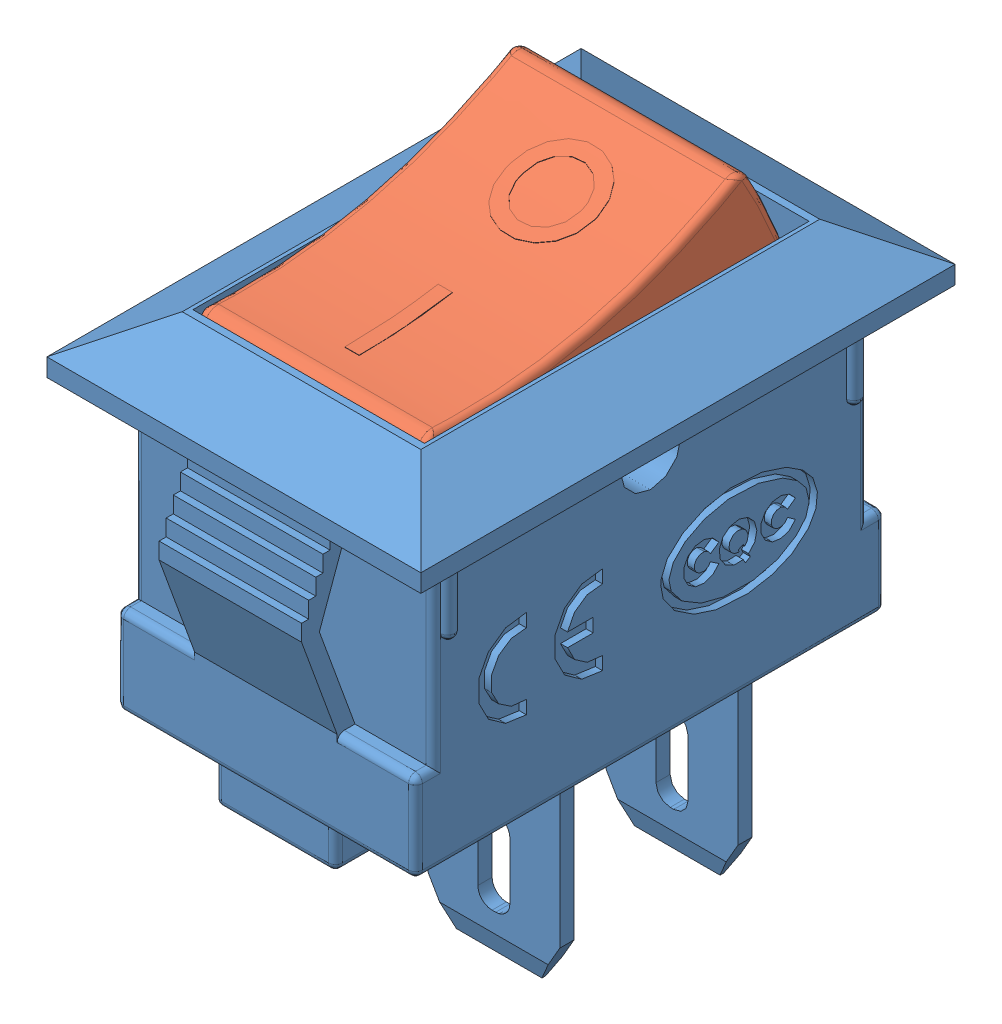
SolidWorks assembly KCD1-11-2P-On, configuration Default. Lengths in mm.
Overall size (10.5 19.01 15.2).
5 component instances, 4 part files, 0 mates.
Components (placement in the parent):
- KCD1-11-2P-On(2)^KCD1-11-2P-On-1: KCD1-11-2P-On(2)^KCD1-11-2P-On [Default] at origin size (10.5 19.01 15.2) (virtual)
  - KCD1-11-2P-On-prt0^KCD1-11-2P-On(2)_KCD1-11-2P-On-1: KCD1-11-2P-On-prt0^KCD1-11-2P-On(2)_KCD1-11-2P-On [Default] at origin size (10.5 16.7 15.2) (virtual)
  - KCD1-11-2P-On-prt1^KCD1-11-2P-On(2)_KCD1-11-2P-On-1: KCD1-11-2P-On-prt1^KCD1-11-2P-On(2)_KCD1-11-2P-On [Default] at (0 -0.9 0) x (1 0 0) z (0 -0.228555 0.973531) size (7.4 7.35 10.6) (virtual)
  - KCD1-11-2P-On-prt2^KCD1-11-2P-On(2)_KCD1-11-2P-On-1: KCD1-11-2P-On-prt2^KCD1-11-2P-On(2)_KCD1-11-2P-On [Default] at (0 -4.8504 -0.3584) x (1 0 0) z (0 0.285651 0.958334) size (5.24 1.4 9.6) (virtual)
  - KCD1-11-2P-On-prt3^KCD1-11-2P-On(2)_KCD1-11-2P-On-1: KCD1-11-2P-On-prt3^KCD1-11-2P-On(2)_KCD1-11-2P-On [Default] at (0 0.1321 0.2423) x (1 0 0) z (0 -0.228555 0.973531) size (2.38 6.89 2.38) (virtual)
